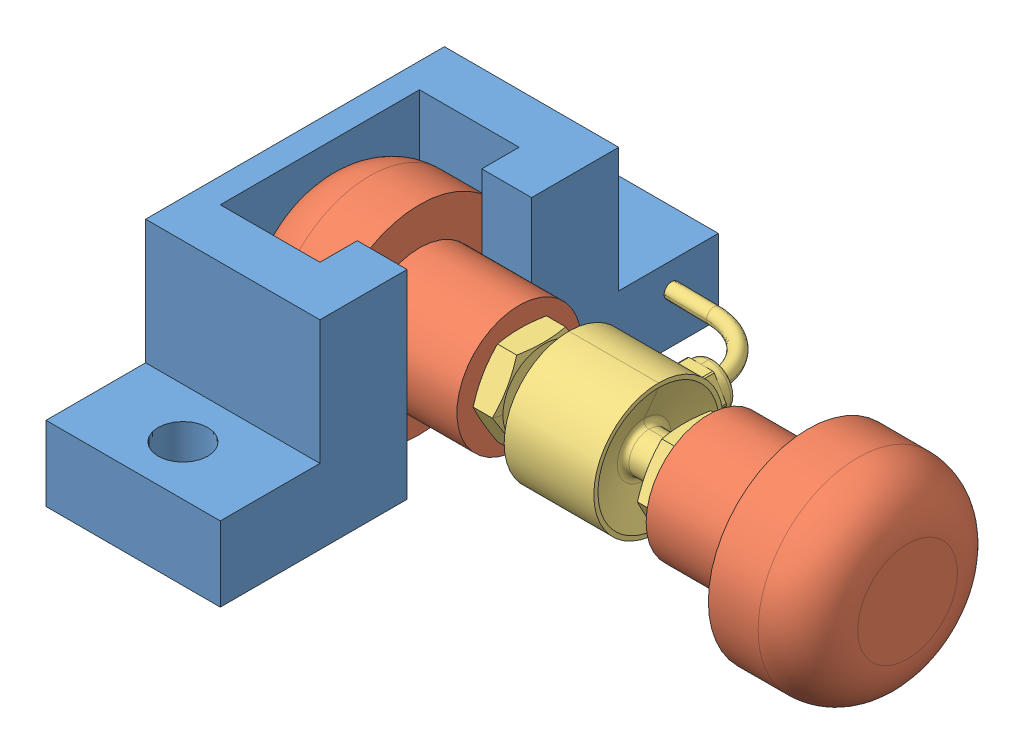
SolidWorks assembly Mont2, configuration Valor predeterminado. Lengths in mm.
Overall size (123 52.27 100).
34 component instances, 7 part files, 14 mates.
Components (placement in the parent):
- Montagem_plataforma_patins-1: Montagem_plataforma_patins [Valor predeterminado] at (37.4421 -415.1457 83.8977) x (0 0 -1) z (1 0 0) size (315 49.52 108.05) (hidden)
  - Plataforma-1: Plataforma [Valor predeterminado] at (-35.8421 -14.4528 149.5555) size (315 19.02 100)
  - KRH25-FL-N-Z0-1: KRH25-FL-N-Z0 [Valor predeterminado] at (79.1579 -44.9528 191.5555) x (0 0 -1) z (0 1 0) size (96 70 30.5)
  - KRH25-FL-N-Z0-2: KRH25-FL-N-Z0 [Valor predeterminado] at (-150.8421 -44.9528 107.5055) x (0 0 1) z (0 1 0) size (96 70 30.5)
  - Allen_M6x30-1: Allen_M6x30 [Valor predeterminado] at (107.6579 -33.4328 127.0555) x (1 0 0) z (0 1 0) size (10 10 38)
  - Allen_M6x30-2: Allen_M6x30 [Valor predeterminado] at (107.6579 -33.4328 172.0555) x (1 0 0) z (0 1 0) size (10 10 38)
  - Allen_M6x30-3: Allen_M6x30 [Valor predeterminado] at (-179.3421 -33.4328 172.0055) x (1 0 0) z (0 1 0) size (10 10 38)
  - Allen_M6x30-4: Allen_M6x30 [Valor predeterminado] at (-122.3421 -33.4328 172.0055) x (1 0 0) z (0 1 0) size (10 10 38)
  - Allen_M6x30-5: Allen_M6x30 [Valor predeterminado] at (-179.3421 -33.4328 127.0055) x (1 0 0) z (0 1 0) size (10 10 38)
  - Allen_M6x30-6: Allen_M6x30 [Valor predeterminado] at (-122.3421 -33.4328 127.0055) x (1 0 0) z (0 1 0) size (10 10 38)
  - Allen_M6x30-7: Allen_M6x30 [Valor predeterminado] at (50.6579 -33.4328 127.0555) x (1 0 0) z (0 1 0) size (10 10 38)
  - Allen_M6x30-8: Allen_M6x30 [Valor predeterminado] at (50.6579 -33.4328 172.0555) x (1 0 0) z (0 1 0) size (10 10 38)
- Montagem_plataforma_patins-2: Montagem_plataforma_patins [Valor predeterminado] at (-121.5579 -415.1457 83.898) x (-0.000002 0 -1) z (1 0 -0.000002) size (315 49.52 108.05) (hidden)
  - Plataforma-1: Plataforma [Valor predeterminado] at (-35.8421 -14.4528 149.5555) size (315 19.02 100)
  - KRH25-FL-N-Z0-1: KRH25-FL-N-Z0 [Valor predeterminado] at (79.1579 -44.9528 191.5555) x (0 0 -1) z (0 1 0) size (96 70 30.5)
  - KRH25-FL-N-Z0-2: KRH25-FL-N-Z0 [Valor predeterminado] at (-150.8421 -44.9528 107.5055) x (0 0 1) z (0 1 0) size (96 70 30.5)
  - Allen_M6x30-1: Allen_M6x30 [Valor predeterminado] at (107.6579 -33.4328 127.0555) x (1 0 0) z (0 1 0) size (10 10 38)
  - Allen_M6x30-2: Allen_M6x30 [Valor predeterminado] at (107.6579 -33.4328 172.0555) x (1 0 0) z (0 1 0) size (10 10 38)
  - Allen_M6x30-3: Allen_M6x30 [Valor predeterminado] at (-179.3421 -33.4328 172.0055) x (1 0 0) z (0 1 0) size (10 10 38)
  - Allen_M6x30-4: Allen_M6x30 [Valor predeterminado] at (-122.3421 -33.4328 172.0055) x (1 0 0) z (0 1 0) size (10 10 38)
  - Allen_M6x30-5: Allen_M6x30 [Valor predeterminado] at (-179.3421 -33.4328 127.0055) x (1 0 0) z (0 1 0) size (10 10 38)
  - Allen_M6x30-6: Allen_M6x30 [Valor predeterminado] at (-122.3421 -33.4328 127.0055) x (1 0 0) z (0 1 0) size (10 10 38)
  - Allen_M6x30-7: Allen_M6x30 [Valor predeterminado] at (50.6579 -33.4328 127.0555) x (1 0 0) z (0 1 0) size (10 10 38)
  - Allen_M6x30-8: Allen_M6x30 [Valor predeterminado] at (50.6579 -33.4328 172.0555) x (1 0 0) z (0 1 0) size (10 10 38)
- Montagem_célula_de_carga-1: Montagem_célula_de_carga [Valor predeterminado] at (-39.0025 -406.2767 139.9526) x (0 0 -1) z (1 0 0) size (100 52.27 234.41)
  - Alojamento_acomplamento-1: Alojamento_acomplamento [Valor predeterminado] at (20.2128 15.6982 82.5001) size (100 39.97 35)
  - Alojamento_acomplamento-2: Alojamento_acomplamento [Valor predeterminado] at (20.2128 15.6982 210.5) x (-1 0 0) z (0 0 -1) size (100 39.97 35) (hidden)
  - Acomplamento_celula_mola-1: Acomplamento_celula_mola [Valor predeterminado] at (20.2128 15.6982 107.5001) x (-0.923728 -0.383049 0) z (0 0 -1) size (40 40 40)
  - Acomplamento_celula_mola-2: Acomplamento_celula_mola [Valor predeterminado] at (20.2128 15.6982 185.5) x (-1 0 0) z (0 0 1) size (40 40 40)
  - U9C_G_5kN-1: U9C_G_5kN [Valor predeterminado] at (20.2128 15.6982 137.5001) size (45.3 26.62 60.01)
- DIN912_ISO 4762 - B-2: DIN912_ISO 4762 - B [ISO 4762 M10 x 50] at (60.9976 -385.5785 159.7398) x (0 -1 0) z (0 0 1) size (60 16 16) (hidden)
- DIN912_ISO 4762 - B-3: DIN912_ISO 4762 - B [ISO 4762 M10 x 50] at (153.9976 -385.5785 159.7398) x (0 -1 0) z (0 0 1) size (60 16 16) (hidden)
- DIN912_ISO 4762 - B-4: DIN912_ISO 4762 - B [ISO 4762 M10 x 50] at (153.9976 -385.5785 79.7398) x (0 -1 0) z (0 0 1) size (60 16 16) (hidden)
- DIN912_ISO 4762 - B-5: DIN912_ISO 4762 - B [ISO 4762 M10 x 50] at (60.9976 -385.5785 79.7398) x (0 -1 0) z (0 0 1) size (60 16 16) (hidden)
Mates (geometry in assembly coordinates):
- Concêntrico1: concentric anti-aligned: circle of Montagem_plataforma_patins-1/Plataforma-1; circle of Montagem_célula_de_carga-1/Alojamento_acomplamento-2
- Concêntrico2: concentric anti-aligned: circle of Montagem_plataforma_patins-1/Plataforma-1; circle of Montagem_célula_de_carga-1/Alojamento_acomplamento-2
- Coincidente4: coincident: plane of Montagem_plataforma_patins-1/Plataforma-1 through (186.9976 -410.5785 119.7398) normal (0 1 0); line of Montagem_célula_de_carga-1/Alojamento_acomplamento-2 through (171.4976 -410.5785 69.7398) axis (0 0 1)
- Concêntrico3: concentric anti-aligned: cylinder of Montagem_plataforma_patins-2/Plataforma-1; cylinder of Montagem_célula_de_carga-1/Alojamento_acomplamento-1 through (60.9976 -360.5785 159.7398) axis (0 -1 0) radius 5
- Concêntrico4: concentric anti-aligned: cylinder of Montagem_plataforma_patins-2/Plataforma-1 through (60.9976 -429.5985 79.7398) axis (0 1 0) radius 5; cylinder of Montagem_célula_de_carga-1/Alojamento_acomplamento-1 through (60.9976 -360.5785 79.7398) axis (0 -1 0) radius 5
- Coincidente6: coincident: plane of Montagem_plataforma_patins-2/Plataforma-1 through (27.9976 -410.5785 119.7398) normal (0 1 0); line of Montagem_célula_de_carga-1/Alojamento_acomplamento-1 through (78.4976 -410.5785 107.2398) axis (0 0 -1)
- Concêntrico61: concentric anti-aligned: cylinder of Montagem_célula_de_carga-1/Alojamento_acomplamento-1 through (60.9976 -360.5785 159.7398) axis (0 -1 0) radius 5; cylinder of DIN912_ISO 4762 - B-2 through (60.9976 -353.8285 159.7398) axis (0 1 0) radius 8
- Coincidente81: coincident anti-aligned: plane of Montagem_célula_de_carga-1/Alojamento_acomplamento-1 through (43.4976 -395.5785 169.7398) normal (0 1 0); plane of DIN912_ISO 4762 - B-2 through (68.9976 -395.5785 159.7398) normal (0 -1 0)
- Concêntrico71: concentric anti-aligned: cylinder of Montagem_célula_de_carga-1/Alojamento_acomplamento-2 through (153.9976 -360.5785 159.7398) axis (0 -1 0) radius 5; cylinder of DIN912_ISO 4762 - B-3 through (153.9976 -353.8285 159.7398) axis (0 1 0) radius 8
- Coincidente91: coincident anti-aligned: plane of Montagem_célula_de_carga-1/Alojamento_acomplamento-2 through (136.4976 -395.5785 169.7398) normal (0 1 0); plane of DIN912_ISO 4762 - B-3 through (161.9976 -395.5785 159.7398) normal (0 -1 0)
- Concêntrico81: concentric anti-aligned: cylinder of Montagem_célula_de_carga-1/Alojamento_acomplamento-2 through (153.9976 -360.5785 79.7398) axis (0 -1 0) radius 5; cylinder of DIN912_ISO 4762 - B-4 through (153.9976 -353.8285 79.7398) axis (0 1 0) radius 8
- Coincidente101: coincident anti-aligned: plane of Montagem_célula_de_carga-1/Alojamento_acomplamento-2 through (171.4976 -395.5785 69.7398) normal (0 1 0); plane of DIN912_ISO 4762 - B-4 through (161.9976 -395.5785 79.7398) normal (0 -1 0)
- Concêntrico91: concentric anti-aligned: cylinder of Montagem_célula_de_carga-1/Alojamento_acomplamento-1 through (60.9976 -360.5785 79.7398) axis (0 -1 0) radius 5; cylinder of DIN912_ISO 4762 - B-5 through (60.9976 -353.8285 79.7398) axis (0 1 0) radius 8
- Coincidente111: coincident anti-aligned: plane of Montagem_célula_de_carga-1/Alojamento_acomplamento-1 through (78.4976 -395.5785 69.7398) normal (0 1 0); plane of DIN912_ISO 4762 - B-5 through (68.9976 -395.5785 79.7398) normal (0 -1 0)
